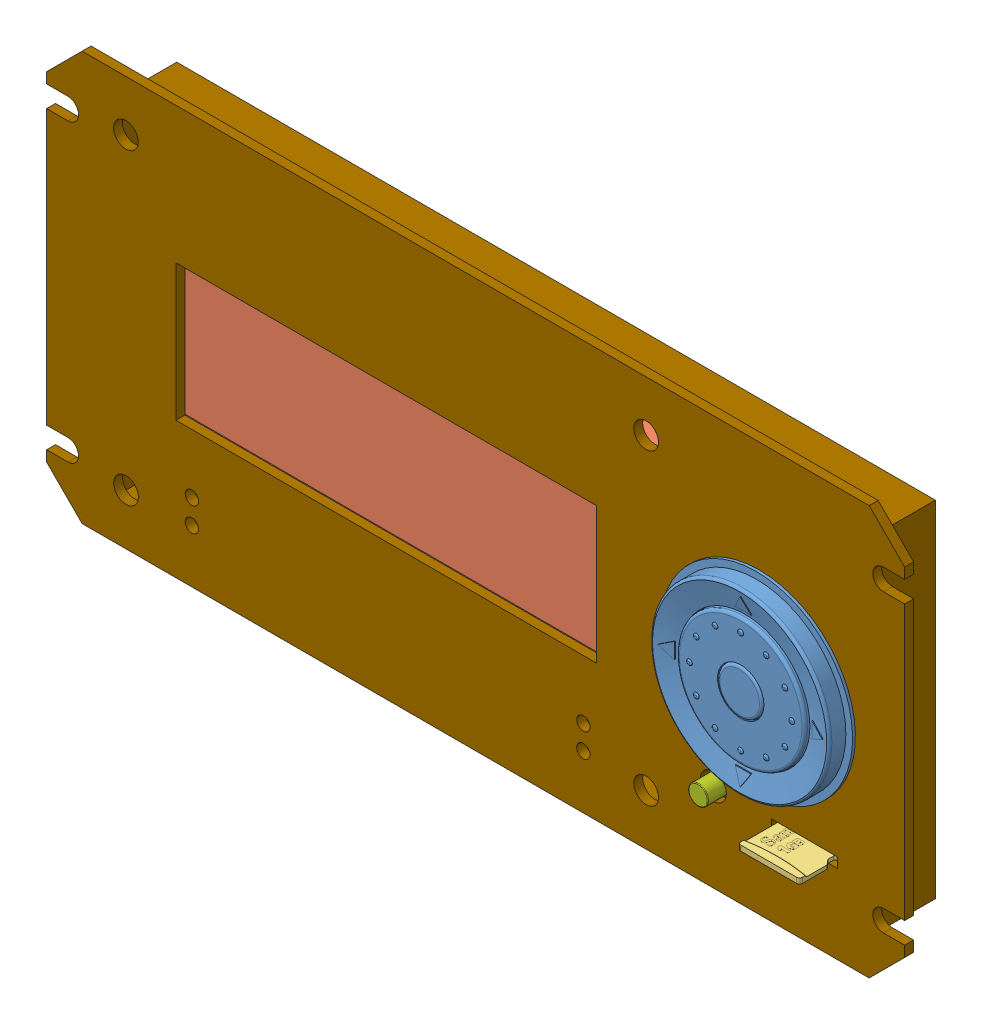
SolidWorks assembly ViKi LCD, configuration Default. Lengths in mm.
Overall size (153.42 73.15 22.06).
13 component instances, 10 part files, 3 mates.
Components (placement in the parent):
- TSWB-3N-CB222 LFS-1: TSWB-3N-CB222 LFS [Default] at (115.5054 22.4071 21.3327) size (34.4 33.63 5)
- LCD_PCB-1: LCD_PCB [Default] at (48.4357 22.541 8.3834) size (98 60 14)
- Main PCB-1: Main PCB [Default] at (141.1785 -11.5286 20.9836) x (-1 0 0) z (0 0 -1)
- TF slot assm-1: TF slot assm [Default] at (108.8042 -1.2114 13.0518) x (-1 0 0) z (0 0 -1) size (32.07 11.96 20.5)
  - User Library-Micro_SD-1: User Library-Micro_SD [Default] at (-14.5274 1.7305 -6.8905) x (0 0 1) z (-1 0 0) size (15 1 11.33)
  - 473093751-1: 473093751 [Default] at (-14.0468 0.2405 -2.0758) size (11.4 3.75 5.5)
    - 473093751-1: 473093751 [Default] at origin size (11.4 3.75 5.5)
  - pin_header_a-sl254-dg-g04mp1-1: pin_header_a-sl254-dg-g04mp1 [Default] at (8.5658 -2.3633 -5.0916) x (1 0 0) z (0 1 0) size (5.08 9.74 7.5)
  - pin_header_a-sl254-dg-g04mp1-2: pin_header_a-sl254-dg-g04mp1 [Default] at (-4.9776 -2.1458 -5.0876) x (1 0 0) z (0 1 0) size (5.08 9.74 7.5)
  - TF PCB-1: TF PCB [Default] at (-2.7801 -3.0645 1.9483) x (1 0 0) z (0 1 0) size (32.07 11.3 1.91)
  - FSMRA7JH-1: FSMRA7JH [Default] at (1.8518 2.8537 -1.4141) x (-1 0 0) z (0 0 -1) size (8.41 10.52 15.86)
  - Untitled-1: Untitled [Default] at (108.7996 1.2114 13.0533) x (-1 0 0) z (0 0 -1) size (11.4 3.52 5.3)
- Front_Panel-1: Front_Panel [Default] at (141.1731 -11.5633 20.9836) x (-1 0 0) z (0 0 -1) size (153.42 73.15 12.6)
Mates (geometry in assembly coordinates):
- Coincident1: coincident anti-aligned: plane of LCD_PCB-1 through (48.4357 22.541 19.3834) normal (0 0 1); plane of Front_Panel-1 through (141.1731 -11.5633 19.3834) normal (0 0 -1)
- Parallel1: parallel aligned: plane of Front_Panel-1 through (134.0611 53.2067 8.3834) normal (0 1 0); plane of LCD_PCB-1 through (-0.5643 42.541 19.3834) normal (0 1 0)
- Concentric2: concentric aligned: cylinder of TF slot assm-1/FSMRA7JH-1 through (106.9524 1.6423 24.1941) axis (0 0 -1) radius 1.7526; cylinder of Front_Panel-1 through (106.9524 1.6423 19.3834) axis (0 0 -1) radius 2.3429
